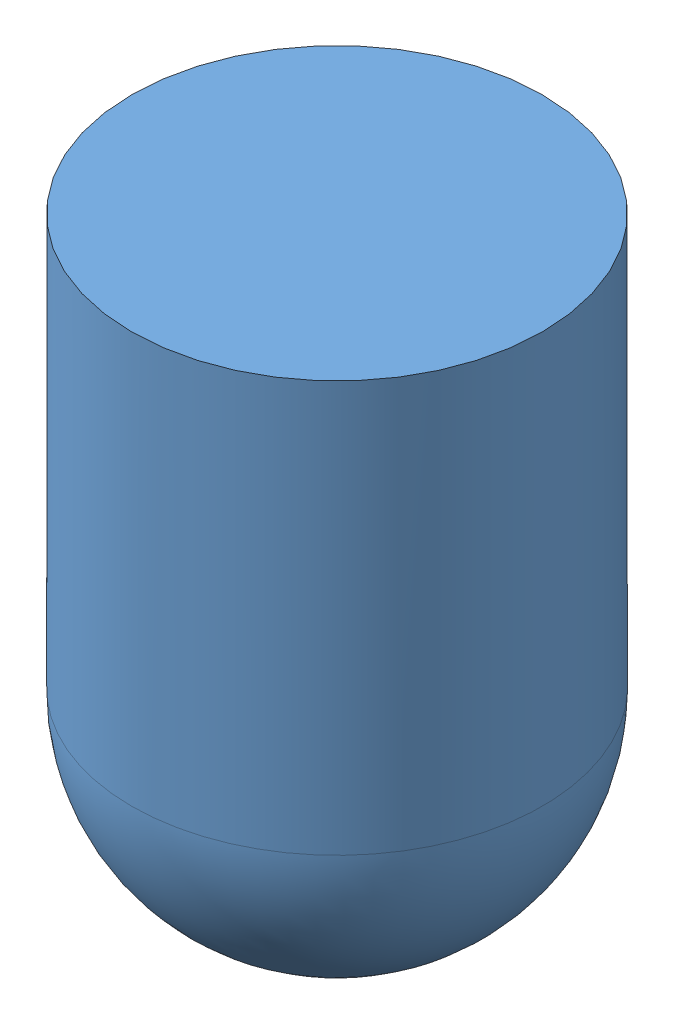
SolidWorks assembly Assem1, configuration Default. Lengths in mm.
Overall size (100 150 100).
4 component instances, 3 part files, 5 mates.
Components (placement in the parent):
- Part2-1: Part2 [Default] at (-8.359 -38.1474 36.703) size (100 150 100)
- Part1-3: Part1 [Default] at (-8.359 -40.6474 36.703) size (80 5 80)
- Part3-1: Part3 [Default] at (-8.359 -45.6474 36.703) size (90 10 90)
- Part3-2: Part3 [Default] at (-8.359 -45.6474 36.703) size (90 10 90)
Mates (geometry in assembly coordinates):
- Distance1: distance = 100 mm: point of Part1-3; plane of Part2-1 through (-8.359 61.8526 36.703) normal (0 1 0)
- Coincident5: coincident: point of Part1-3; point of assembly
- Concentric1: concentric: circle of Part2-1; circle of Part3-1
- Distance2: distance = 97.5 mm aligned: plane of Part3-1 through (-8.359 -35.6474 36.703) normal (0 1 0); plane of Part2-1 through (-8.359 61.8526 36.703) normal (0 1 0)
- Coincident6: coincident aligned: circle of Part3-1; circle of Part3-2
